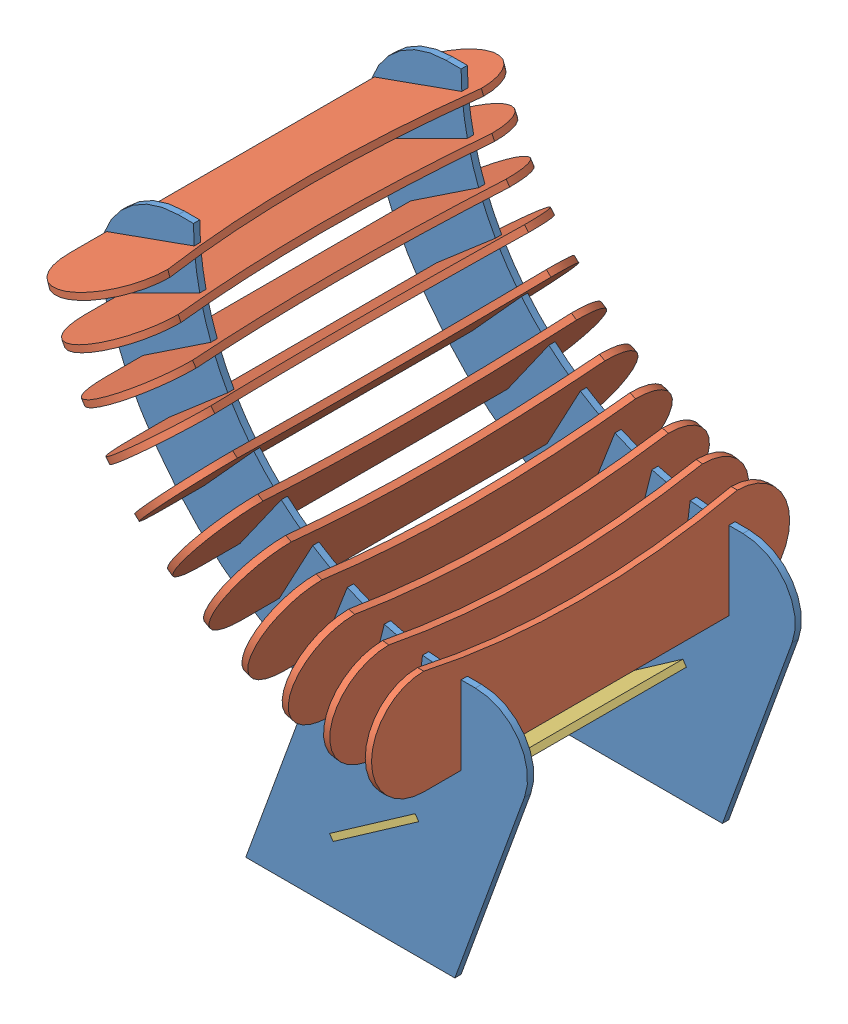
SolidWorks assembly Assem1, configuration Default. Lengths in mm.
Overall size (818.32 1000 800).
14 component instances, 3 part files, 8 mates.
Components (placement in the parent):
- base-1: base [Default] at (603.7313 144.5768 902.293) size (818.32 1000 12)
- S1-1: S1 [Default] at (615.7313 494.5768 685.7334) x (0 0 1) z (-1 0 0) size (800 200 12)
- base-2: base [Default] at (603.7313 144.5768 390.293) size (818.32 1000 12)
- S1-2: S1 [Default] at (524.3184 506.0759 685.7334) x (0 0 1) z (-0.992473 0.122467 0) size (800 200 12)
- S1-3: S1 [Default] at (435.0018 528.6835 685.7334) x (0 0 1) z (-0.970004 0.24309 0) size (800 200 12)
- S1-4: S1 [Default] at (349.1262 562.0593 685.7334) x (0 0 1) z (-0.932932 0.360054 0) size (800 200 12)
- S1-5: S1 [Default] at (267.9844 605.7007 685.7334) x (0 0 1) z (-0.881814 0.471597 0) size (800 200 12)
- S1-6: S1 [Default] at (192.7981 658.9508 685.7334) x (0 0 1) z (-0.817421 0.57604 0) size (800 200 12)
- S1-7: S1 [Default] at (124.6991 721.008 685.7334) x (0 0 1) z (-0.740722 0.671811 0) size (800 200 12)
- S1-8: S1 [Default] at (64.7127 790.9379 685.7334) x (0 0 1) z (-0.652872 0.757468 0) size (800 200 12)
- S1-9: S1 [Default] at (13.7419 867.6877 685.7334) x (0 0 1) z (-0.555193 0.831722 0) size (800 200 12)
- S1-10: S1 [Default] at (-27.4458 950.1021 685.7334) x (0 0 1) z (-0.449155 0.893454 0) size (800 200 12)
- S1-11: S1 [Default] at (-58.2305 1036.9402 685.7334) x (0 0 1) z (-0.336356 0.941735 0) size (800 200 12)
- suport-2: suport [Default] at (534.7599 369.0409 390.293) x (0 0 1) z (-0.573576 0.819152 0) size (524 200 12)
Mates (geometry in assembly coordinates):
- Coincident1: coincident anti-aligned: plane of base-1 through (603.7313 494.5768 914.293) normal (0 1 0); plane of S1-1 through (603.7313 494.5768 385.7334) normal (0 -1 0)
- Coincident2: coincident anti-aligned: plane of base-1 through (603.7313 694.5768 914.293) normal (1 0 0); plane of S1-1 through (603.7313 594.5768 385.7334) normal (-1 0 0)
- Coincident3: coincident aligned: plane of base-1 through (603.7313 144.5768 914.293) normal (0.939693 -0.34202 0); plane of base-2 through (603.7313 144.5768 402.293) normal (0.939693 -0.34202 0)
- Coincident4: coincident aligned: plane of base-1 through (603.7313 144.5768 914.293) normal (0 -1 0); plane of base-2 through (603.7313 144.5768 402.293) normal (0 -1 0)
- width: distance = 500 mm anti-aligned: plane of base-1 through (642.9016 544.5768 902.293) normal (0 0 -1); plane of base-2 through (642.9016 544.5768 402.293) normal (0 0 1)
- Coincident8: coincident: plane of base-2 through (642.9016 544.5768 390.293) normal (0 0 -1); plane of suport-2 through (527.8769 378.8707 390.293) normal (0 0 -1)
- Coincident9: coincident: plane of base-2 through (370.9294 254.3256 390.293) normal (-0.573576 0.819152 0); plane of suport-2 through (534.7599 369.0409 390.293) normal (0.573576 -0.819152 0)
- Coincident10: coincident: moEndPointRef_w of base-2; line of suport-2 through (527.8769 378.8707 390.293) axis (0.573576 -0.819152 0)
